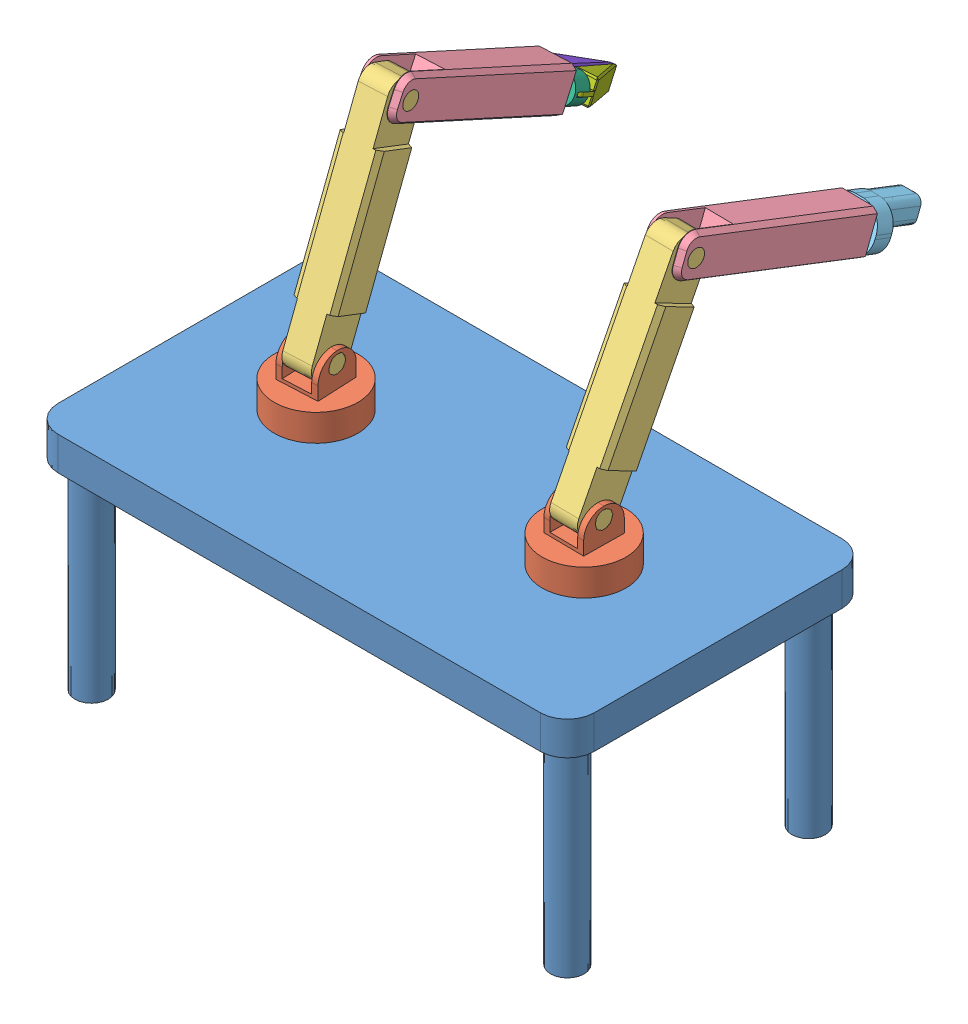
SolidWorks assembly Assem1, configuration Default. Lengths in mm.
Overall size (1600 1830.73 1674.53).
11 component instances, 8 part files, 22 mates.
Components (placement in the parent):
- Base-1: Base [Default] at (795.2493 951.193 1214.533) size (1600 700 900)
- Link 1-1: Link 1 [Default] at (395.2493 1051.193 1214.533) x (-0.048313 0 -0.998832) z (0.998832 0 -0.048313) size (250 260 250)
- Link 1-2: Link 1 [Default] at (1195.2493 1051.193 1214.533) x (0.011557 0 -0.999933) z (0.999933 0 0.011557) size (250 260 250)
- Link 2-1: Link 2 [Default] at (396.1165 1152.7336 1232.4608) x (-0.998832 0 0.048313) z (-0.044654 -0.381727 -0.923196) size (120 700 120)
- Link 2-2: Link 2 [Default] at (1195.0054 1154.1775 1235.6403) x (-0.999933 0 -0.011557) z (0.010327 -0.44893 -0.893507) size (120 700 120)
- Link 3-1: Link 3 [Default] at (1197.8852 1754.3437 986.4744) x (0.999933 0 0.011557) z (0.004101 0.934923 -0.354826) size (120 600 120)
- Link 3-2: Link 3 [Default] at (386.1208 1776.6675 1025.8061) x (0.998832 0 -0.048313) z (-0.020962 0.900974 -0.433367) size (120 600 120)
- Left End Effector-2: Left End Effector [Default] at (1204.9086 1523.6915 378.8148) x (0.999933 0 0.011557) z (-0.004101 -0.934923 0.354826) size (145 275 130)
- Right End Effector-2: Right End Effector [Default] at (357.8273 1494.6499 440.8569) x (0.998832 0 -0.048313) z (0.020962 -0.900974 0.433367) size (150 130 80)
- Gripper Claw-5: Gripper Claw [Default] at (381.6073 1518.4303 408.3833) x (0.997111 -0.012811 -0.074864) z (-0.073002 -0.433684 -0.898103) size (70 70 206.48)
- Gripper Claw Right -4: Gripper Claw Right  [Default] at (332.0875 1455.1497 440.7436) x (-0.999423 -0.007294 0.033177) z (-0.026731 -0.433812 -0.900607) size (70 70 206.48)
Mates (geometry in assembly coordinates):
- Concentric1: concentric aligned: cylinder of Base-1 through (395.2493 961.193 1214.533) axis (0 1 0) radius 75; cylinder of Link 1-1 through (395.2493 971.193 1214.533) axis (0 1 0) radius 50
- Coincident1: coincident anti-aligned: plane of Base-1 through (795.2493 1051.193 1214.533) normal (0 1 0); plane of Link 1-1 through (395.2493 1051.193 1214.533) normal (0 -1 0)
- Concentric2: concentric aligned: cylinder of Base-1 through (1195.2493 961.193 1214.533) axis (0 1 0) radius 75; cylinder of Link 1-2 through (1195.2493 971.193 1214.533) axis (0 1 0) radius 50
- Coincident2: coincident anti-aligned: plane of Base-1 through (795.2493 1051.193 1214.533) normal (0 1 0); plane of Link 1-2 through (1195.2493 1051.193 1214.533) normal (0 -1 0)
- Concentric3: concentric aligned: cylinder of Link 1-1 through (325.3311 1196.193 1217.9149) axis (0.998832 0 -0.048313) radius 25; cylinder of Link 2-1 through (335.3194 1196.193 1217.4317) axis (0.998832 0 -0.048313) radius 25
- Coincident3: coincident anti-aligned: plane of Link 1-1 through (440.0991 1141.193 1272.4338) normal (-0.998832 0 0.048313); plane of Link 2-1 through (437.7959 1323.5212 1224.8184) normal (0.998832 0 -0.048313)
- Concentric5: concentric anti-aligned: cylinder of Link 1-2 through (1125.254 1196.193 1213.724) axis (0.999933 0 0.011557) radius 25; cylinder of Link 2-2 through (1255.2453 1196.193 1215.2264) axis (-0.999933 0 -0.011557) radius 26.2285
- Coincident4: coincident anti-aligned: plane of Link 1-2 through (1236.5531 1141.193 1275.0144) normal (-0.999933 0 -0.011557); plane of Link 2-2 through (1237.2131 1324.084 1217.912) normal (0.999933 0 0.011557)
- Concentric6: concentric aligned: cylinder of Link 2-2 through (1258.3893 1737.6587 943.2107) axis (-0.999933 0 -0.011557) radius 25; cylinder of Link 3-1 through (1318.3853 1737.6587 943.9041) axis (-0.999933 0 -0.011557) radius 25
- Coincident5: coincident anti-aligned: plane of Link 2-2 through (1239.1847 1663.6394 1047.3299) normal (0.999933 0 0.011557); plane of Link 3-1 through (1241.3652 1641.4724 858.6716) normal (-0.999933 0 -0.011557)
- Concentric7: concentric anti-aligned: cylinder of Link 2-1 through (324.1441 1756.2668 986.3905) axis (0.998832 0 -0.048313) radius 25; cylinder of Link 3-2 through (503.9339 1756.2668 977.6943) axis (-0.998832 0 0.048313) radius 25
- Coincident6: coincident anti-aligned: plane of Link 2-1 through (346.886 1674.7458 1083.9898) normal (-0.998832 0 0.048313); plane of Link 3-2 through (338.463 1653.1893 909.8497) normal (0.998832 0 -0.048313)
- Concentric12: concentric aligned: cylinder of Link 3-1 through (1203.2878 1576.919 519.0439) axis (0.010805 -0.35485 -0.934861) radius 25; cylinder of Left End Effector-2 through (1203.2878 1576.919 519.0439) axis (0.010805 -0.35485 -0.934861) radius 25
- Coincident12: coincident anti-aligned: plane of Link 3-1 through (1204.3683 1541.434 425.5578) normal (0.010805 -0.35485 -0.934861); plane of Left End Effector-2 through (1204.3683 1541.434 425.5578) normal (-0.010805 0.35485 0.934861)
- Parallel3: parallel aligned: plane of Link 3-1 through (1144.6184 1597.5294 403.5748) normal (0.004101 0.934923 -0.354826); plane of Left End Effector-2 through (1132.1397 1602.204 401.6562) normal (0.004101 0.934923 -0.354826)
- Concentric15: concentric aligned: cylinder of Right End Effector-2 through (421.9395 1514.272 441.6301) axis (0.020962 -0.900974 0.433367) radius 7.5; cylinder of Gripper Claw-5 through (421.9604 1513.371 442.0635) axis (0.020962 -0.900974 0.433367) radius 7.5
- Width2: width aligned: plane of Right End Effector-2 through (434.6066 1506.599 475.8305) normal (-0.020962 0.900974 -0.433367); plane of Gripper Claw-5 through (434.355 1517.4107 470.6301) normal (0.020962 -0.900974 0.433367); plane of Right End Effector-2 through (382.2152 1492.302 420.9509) normal (-0.020962 0.900974 -0.433367); plane of Gripper Claw-5 through (382.4667 1481.4903 426.1513) normal (0.020962 -0.900974 0.433367)
- Concentric16: concentric anti-aligned: cylinder of Right End Effector-2 through (294.0889 1514.272 447.8141) axis (0.020962 -0.900974 0.433367) radius 7.5; cylinder of Gripper Claw Right -4 through (294.7388 1486.3418 461.2485) axis (-0.020962 0.900974 -0.433367) radius 7.5
- Width3: width anti-aligned: plane of Right End Effector-2 through (284.5302 1517.4107 477.877) normal (0.020962 -0.900974 0.433367); plane of Gripper Claw Right -4 through (284.7817 1506.599 483.0774) normal (-0.020962 0.900974 -0.433367); plane of Right End Effector-2 through (331.2281 1492.0896 422.9755) normal (-0.020962 0.900974 -0.433367); plane of Gripper Claw Right -4 through (331.4796 1481.2779 428.1759) normal (0.020962 -0.900974 0.433367)
- Concentric18: concentric aligned: cylinder of Link 3-2 through (364.3565 1559.7309 575.8452) axis (-0.043528 -0.433873 -0.899922) radius 25; cylinder of Right End Effector-2 through (363.486 1551.0534 557.8468) axis (-0.043528 -0.433873 -0.899922) radius 25
- Coincident15: coincident anti-aligned: plane of Link 3-2 through (360.0037 1516.3436 485.853) normal (-0.043528 -0.433873 -0.899922); plane of Right End Effector-2 through (360.0037 1516.3436 485.853) normal (0.043528 0.433873 0.899922)
- Parallel5: parallel aligned: plane of Link 3-2 through (298.816 1570.402 462.7498) normal (-0.020962 0.900974 -0.433367); plane of Right End Effector-2 through (284.2528 1552.3825 472.1418) normal (-0.020962 0.900974 -0.433367)
